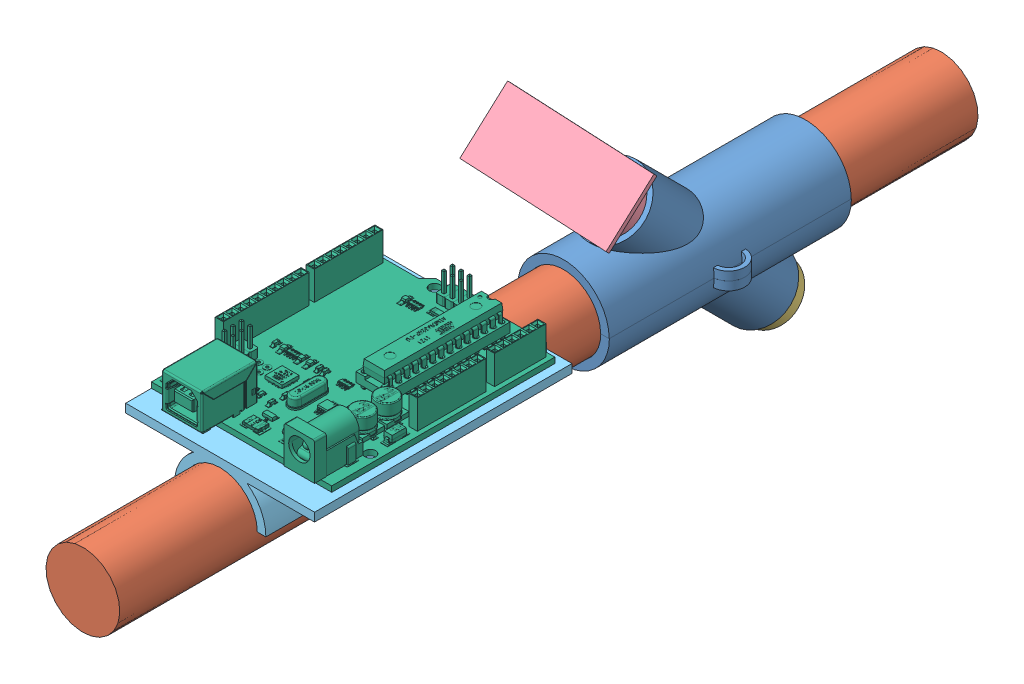
SolidWorks assembly assembly, configuration Default. Lengths in mm.
Overall size (62.55 66.63 254).
7 component instances, 6 part files, 13 mates.
Components (placement in the parent):
- v1-1: v1 [Default] at (52.417 79.6375 18.7509) size (35.64 28.62 71.63)
- v1-2: v1 [Default] at (52.417 79.6375 176.8034) x (1 0 0) z (0 0 -1) size (35.64 28.62 71.63)
- pipe-1: pipe [Default] at (52.417 79.6375 21.8455) x (0.739982 0.672627 0) z (0 0 1) size (21.84 21.84 254)
- reciever-1: reciever [Default] at (52.417 54.4928 72.6324) x (-0.92623 0.26655 -0.26655) z (0 0.707107 0.707107) size (17.02 17.02 11)
- transmitter-1: transmitter [Default] at (62.2282 98.6913 130.8089) x (-0.999354 0.025408 -0.025408) z (0 -0.707107 -0.707107) size (44.45 19.05 12.27)
- arduino-holder-1: arduino-holder [Default] at (52.417 79.6375 159.0234) size (55.88 13.54 76.2)
- arduino uno-1: arduino uno [Default] at (77.817 94.8275 227.6034) size (53.34 15.25 74.93)
Mates (geometry in assembly coordinates):
- Coincident1: coincident anti-aligned: plane of v1-1 through (41.417 79.6375 94.9509) normal (0 1 0); plane of v1-2 through (41.417 79.6375 100.6034) normal (0 -1 0)
- Concentric1: concentric anti-aligned: cylinder of v1-1 through (52.417 80.9733 99.1129) axis (0 -0.707107 -0.707107) radius 8.5; cylinder of v1-2 through (52.417 78.3018 96.4414) axis (0 0.707107 0.707107) radius 8.5
- Concentric2: concentric anti-aligned: cylinder of v1-2 through (52.417 79.6375 100.6034) axis (0 0 1) radius 11; cylinder of pipe-1 through (52.417 79.6375 275.8455) axis (0 0 -1) radius 10.922
- Concentric3: concentric aligned: cylinder of v1-1 through (52.417 80.9733 99.1129) axis (0 -0.707107 -0.707107) radius 8.5; cylinder of reciever-1 through (52.417 62.271 80.4106) axis (0 -0.707107 -0.707107) radius 8.509
- Distance1: distance = 5.08 mm aligned: plane of reciever-1 through (52.417 54.4928 72.6324) normal (0 -0.707107 -0.707107); plane of v1-1 through (52.417 58.0849 76.2245) normal (0 -0.707107 -0.707107)
- Concentric4: concentric aligned: cylinder of v1-2 through (52.417 78.3018 96.4414) axis (0 0.707107 0.707107) radius 8.5; cylinder of transmitter-1 through (52.417 97.0041 115.1437) axis (0 0.707107 0.707107) radius 8.5
- Distance2: distance = 5.08 mm anti-aligned: plane of transmitter-1 through (62.2282 97.7933 129.9109) normal (0 -0.707107 -0.707107); plane of v1-2 through (52.417 101.1902 119.3298) normal (0 0.707107 0.707107)
- Concentric5: concentric aligned: cylinder of pipe-1 through (52.417 79.6375 275.8455) axis (0 0 -1) radius 10.922; cylinder of arduino-holder-1 through (52.417 79.6375 239.2399) axis (0 0 -1) radius 11
- Coincident6: coincident aligned: plane of arduino-holder-1 through (24.477 90.6375 239.2399) normal (-1 0 0); plane of arduino uno-1 through (24.477 93.1775 231.6199) normal (-1 0 0)
- Coincident7: coincident aligned: plane of arduino-holder-1 through (52.417 79.6375 163.0399) normal (0 0 -1); plane of arduino uno-1 through (72.737 93.1775 163.0399) normal (0 0 -1)
- Coincident10: coincident anti-aligned: plane of arduino-holder-1 through (80.357 93.1775 235.2234) normal (0 1 0); plane of arduino uno-1 through (77.817 93.1775 227.6034) normal (0 -1 0)
- Coincident11: coincident aligned: line of v1-1 through (38.877 79.6375 133.5589) axis (0 0 -1); line of arduino-holder-1 through (38.877 79.6375 235.2234) axis (0 0 -1)
- Distance3: distance = 25.4 mm anti-aligned: plane of arduino-holder-1 through (52.417 79.6375 159.0234) normal (0 0 -1); plane of v1-2 through (52.417 79.6375 133.6234) normal (0 0 1)
